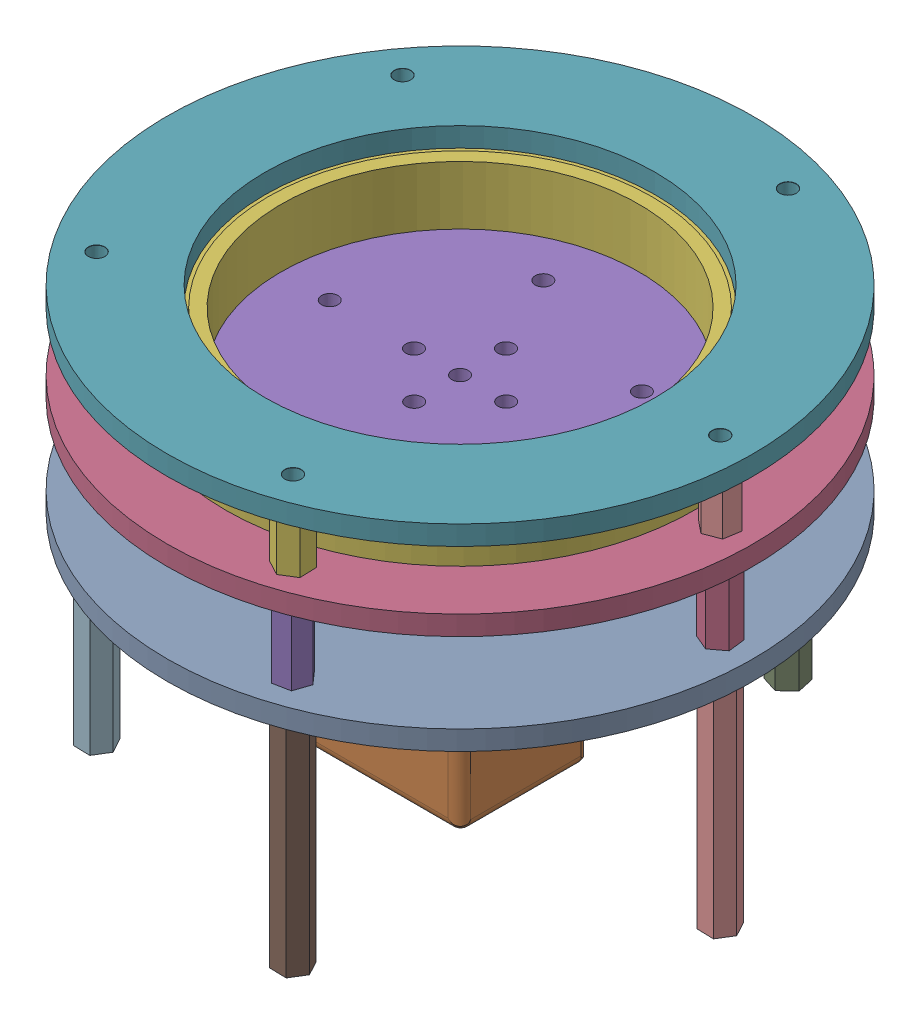
SolidWorks assembly 云台, configuration 默认. Lengths in mm.
Overall size (90 65.3 90).
22 component instances, 9 part files, 49 mates.
Components (placement in the parent):
- 底盘-1: 底盘 [默认] at (18.7397 -12.0246 45) size (90 3 90)
- 舵机td8820-1: 舵机td8820 [默认] at (8.8197 -24.5424 45) size (54.61 46.91 20)
- 舵机舵盘-1: 舵机舵盘 [默认] at (18.7397 -1.3296 45) x (0.999999 0 -0.001681) z (0.001681 0 0.999999) size (19.8 4.6 19.8)
- 云台大盘-1: 云台大盘 [默认] at (18.7397 3.2704 45) size (90 3 90)
- 云台小盘下-1: 云台小盘下 [默认] at (18.7397 6.2704 45) x (-0.999999 0 0.001681) z (0.001681 0 0.999999) size (59 3 59)
- 云台轴承-1: 云台轴承 [默认] at (18.7397 10.7704 45) size (72 9 72)
- 云台大盘-2: 云台大盘 [默认] at (18.7397 15.2704 45) size (90 3 90)
- m3+6铜柱长35-1: m3+6铜柱长35 [默认] at (-13.621 -47.0246 21.4886) x (0.476022 0 0.879433) z (0 1 0) size (5.2 4.5 41)
- m3+6铜柱长35-2: m3+6铜柱长35 [默认] at (31.1004 -47.0246 6.9577) x (0.738621 0 -0.674121) z (0 1 0) size (5.2 4.5 41)
- m3+6铜柱长35-3: m3+6铜柱长35 [默认] at (58.7397 -47.0246 45) x (0.476022 0 0.879433) z (0 1 0) size (5.2 4.5 41)
- m3+6铜柱长35-4: m3+6铜柱长35 [默认] at (31.1004 -47.0246 83.0423) x (0.476022 0 0.879433) z (0 1 0) size (5.2 4.5 41)
- m3+6铜柱长35-5: m3+6铜柱长35 [默认] at (-13.621 -47.0246 68.5114) x (0.476022 0 0.879433) z (0 1 0) size (5.2 4.5 41)
- m3+6铜柱长12-1: m3+6铜柱长12 [默认] at (31.1004 -8.7296 6.9577) x (1 0 0) z (0 1 0) size (5.2 4.5 18)
- m3+6铜柱长12-2: m3+6铜柱长12 [默认] at (-13.621 -8.7296 21.4886) x (-0.864717 0 -0.502259) z (0 1 0) size (5.2 4.5 18)
- m3+6铜柱长12-3: m3+6铜柱长12 [默认] at (-13.621 -8.7296 68.5114) x (0.977179 0 -0.212417) z (0 1 0) size (5.2 4.5 18)
- m3+6铜柱长12-4: m3+6铜柱长12 [默认] at (58.7397 -8.7296 45) x (-0.920293 0 -0.391229) z (0 1 0) size (5.2 4.5 18)
- m3+6铜柱长12-5: m3+6铜柱长12 [默认] at (31.1004 -8.7296 83.0423) x (-0.980793 0 0.195053) z (0 1 0) size (5.2 4.5 18)
- m3母铜柱长9-1: m3母铜柱长9 [默认] at (31.1004 6.2704 83.0423) x (-0.882048 0 -0.471159) z (0 1 0) size (5.2 4.5 9)
- m3母铜柱长9-2: m3母铜柱长9 [默认] at (-13.621 6.2704 21.4886) x (-0.654117 0 -0.756393) z (0 1 0) size (5.2 4.5 9)
- m3母铜柱长9-3: m3母铜柱长9 [默认] at (-13.621 6.2704 68.5114) x (-0.91723 0 -0.398357) z (0 1 0) size (5.2 4.5 9)
- m3母铜柱长9-4: m3母铜柱长9 [默认] at (31.1004 6.2704 6.9577) x (-0.720779 0 -0.693165) z (0 1 0) size (5.2 4.5 9)
- m3母铜柱长9-5: m3母铜柱长9 [默认] at (58.7397 6.2704 45) x (-0.935329 0 0.35378) z (0 1 0) size (5.2 4.5 9)
Mates (geometry in assembly coordinates):
- 重合1: coincident anti-aligned: plane of 底盘-1 through (-11.1803 -12.0246 55) normal (0 0 -1); plane of 舵机td8820-1 through (8.8197 -24.5424 55) normal (0 0 1)
- 重合2: coincident anti-aligned: plane of 底盘-1 through (-11.1803 -12.0246 35) normal (1 0 0); plane of 舵机td8820-1 through (-11.1803 -45.1346 55) normal (-1 0 0)
- 重合3: coincident anti-aligned: plane of 底盘-1 through (18.7397 -12.0246 45) normal (0 -1 0); plane of 舵机td8820-1 through (-18.4853 -12.0246 55) normal (0 1 0)
- 同心1: concentric aligned: circle of 云台轴承-1; circle of 云台大盘-2
- 同心2: concentric aligned: circle of 云台大盘-1; circle of 云台轴承-1
- 重合4: coincident anti-aligned: plane of 云台大盘-1 through (18.7397 6.2704 45) normal (0 1 0); plane of 云台轴承-1 through (18.7397 6.2704 45) normal (0 -1 0)
- 重合5: coincident anti-aligned: plane of 云台轴承-1 through (18.7397 15.2704 45) normal (0 1 0); plane of 云台大盘-2 through (18.7397 15.2704 45) normal (0 -1 0)
- 同心3: concentric aligned: circle of 云台大盘-1; circle of 云台大盘-2
- 同心4: concentric aligned: circle of 云台大盘-1; circle of 云台大盘-2
- 同心5: concentric aligned: circle of 云台大盘-1; circle of 云台大盘-2
- 相切1: tangent aligned: cylinder of 舵机舵盘-1 through (18.7397 11.0486 45) axis (0 -1 0) radius 2.75; cylinder of 舵机td8820-1 through (18.7397 -4.9296 45) axis (0 -1 0) radius 2.75
- 距离1: distance = 1 mm anti-aligned: plane of 舵机td8820-1 through (18.7397 1.7704 45) normal (0 1 0); plane of 舵机舵盘-1 through (18.7397 2.7704 45) normal (0 -1 0)
- 重合11: coincident anti-aligned: plane of 舵机舵盘-1 through (18.7397 3.2704 45) normal (0 1 0); plane of 云台小盘下-1 through (18.7397 3.2704 45) normal (0 -1 0)
- 同心6: concentric anti-aligned: circle of 舵机舵盘-1; circle of 云台小盘下-1
- 同心7: concentric anti-aligned: circle of 舵机舵盘-1; circle of 云台小盘下-1
- 重合13: coincident anti-aligned: plane of 云台小盘下-1 through (18.7397 6.2704 45) normal (0 1 0); plane of 云台轴承-1 through (18.7397 6.2704 45) normal (0 -1 0)
- 同心8: concentric anti-aligned: circle of 云台小盘下-1; circle of 云台轴承-1
- 同心9: concentric anti-aligned: circle of 底盘-1; circle of 云台大盘-1
- 同心10: concentric anti-aligned: circle of 底盘-1; circle of 云台大盘-1
- 同心11: concentric aligned: cylinder of 底盘-1 through (31.1004 -12.0246 6.9577) axis (0 -1 0) radius 1.25; cylinder of m3+6铜柱长35-2 through (31.1004 -6.0246 6.9577) axis (0 -1 0) radius 1.25
- 重合14: coincident anti-aligned: plane of 底盘-1 through (18.7397 -12.0246 45) normal (0 -1 0); plane of m3+6铜柱长35-2 through (31.1004 -12.0246 6.9577) normal (0 1 0)
- 同心12: concentric aligned: cylinder of 底盘-1 through (-13.621 -12.0246 21.4886) axis (0 -1 0) radius 1.25; cylinder of m3+6铜柱长35-1 through (-13.621 -6.0246 21.4886) axis (0 -1 0) radius 1.25
- 重合15: coincident anti-aligned: plane of 底盘-1 through (18.7397 -12.0246 45) normal (0 -1 0); plane of m3+6铜柱长35-1 through (-13.621 -12.0246 21.4886) normal (0 1 0)
- 同心14: concentric aligned: cylinder of 底盘-1 through (-13.621 -12.0246 68.5114) axis (0 -1 0) radius 1.25; cylinder of m3+6铜柱长35-5 through (-13.621 -6.0246 68.5114) axis (0 -1 0) radius 1.25
- 重合16: coincident anti-aligned: plane of 底盘-1 through (18.7397 -12.0246 45) normal (0 -1 0); plane of m3+6铜柱长35-5 through (-13.621 -12.0246 68.5114) normal (0 1 0)
- 同心15: concentric aligned: cylinder of 底盘-1 through (31.1004 -12.0246 83.0423) axis (0 -1 0) radius 1.25; cylinder of m3+6铜柱长35-4 through (31.1004 -6.0246 83.0423) axis (0 -1 0) radius 1.25
- 重合17: coincident anti-aligned: plane of 底盘-1 through (18.7397 -12.0246 45) normal (0 -1 0); plane of m3+6铜柱长35-4 through (31.1004 -12.0246 83.0423) normal (0 1 0)
- 同心16: concentric aligned: cylinder of 底盘-1 through (58.7397 -12.0246 45) axis (0 -1 0) radius 1.25; cylinder of m3+6铜柱长35-3 through (58.7397 -6.0246 45) axis (0 -1 0) radius 1.25
- 重合18: coincident anti-aligned: plane of 底盘-1 through (18.7397 -12.0246 45) normal (0 -1 0); plane of m3+6铜柱长35-3 through (58.7397 -12.0246 45) normal (0 1 0)
- 同心17: concentric aligned: cylinder of m3+6铜柱长35-3 through (58.7397 -6.0246 45) axis (0 -1 0) radius 1.25; cylinder of m3+6铜柱长12-4 through (58.7397 -8.7296 45) axis (0 -1 0) radius 1.25
- 同心18: concentric anti-aligned: cylinder of 云台大盘-1 through (31.1004 6.2704 6.9577) axis (0 1 0) radius 1.25; cylinder of m3+6铜柱长12-1 through (31.1004 9.2704 6.9577) axis (0 -1 0) radius 1.25
- 重合19: coincident anti-aligned: plane of 云台大盘-1 through (18.7397 3.2704 45) normal (0 -1 0); plane of m3+6铜柱长12-1 through (31.1004 3.2704 6.9577) normal (0 1 0)
- 重合20: coincident anti-aligned: plane of 云台大盘-1 through (18.7397 3.2704 45) normal (0 -1 0); plane of m3+6铜柱长12-4 through (58.7397 3.2704 45) normal (0 1 0)
- 同心19: concentric aligned: cylinder of m3+6铜柱长35-1 through (-13.621 -6.0246 21.4886) axis (0 -1 0) radius 1.25; cylinder of m3+6铜柱长12-2 through (-13.621 -8.7296 21.4886) axis (0 -1 0) radius 1.25
- 重合22: coincident anti-aligned: circle of m3+6铜柱长35-5; cylinder of m3+6铜柱长12-3 through (-13.621 -8.7296 68.5114) axis (0 -1 0) radius 1.25
- 重合23: coincident anti-aligned: plane of 云台大盘-1 through (18.7397 3.2704 45) normal (0 -1 0); plane of m3+6铜柱长12-3 through (-13.621 3.2704 68.5114) normal (0 1 0)
- 同心21: concentric aligned: cylinder of m3+6铜柱长35-4 through (31.1004 -6.0246 83.0423) axis (0 -1 0) radius 1.25; cylinder of m3+6铜柱长12-5 through (31.1004 -8.7296 83.0423) axis (0 -1 0) radius 1.25
- 重合24: coincident anti-aligned: plane of 云台大盘-1 through (18.7397 3.2704 45) normal (0 -1 0); plane of m3+6铜柱长12-5 through (31.1004 3.2704 83.0423) normal (0 1 0)
- 重合25: coincident anti-aligned: plane of 云台大盘-1 through (18.7397 3.2704 45) normal (0 -1 0); plane of m3+6铜柱长12-2 through (-13.621 3.2704 21.4886) normal (0 1 0)
- 同心22: concentric aligned: cylinder of m3+6铜柱长12-4 through (58.7397 9.2704 45) axis (0 -1 0) radius 1.25; cylinder of m3母铜柱长9-5 through (58.7397 6.2704 45) axis (0 -1 0) radius 1.25
- 同心23: concentric aligned: cylinder of m3+6铜柱长12-1 through (31.1004 9.2704 6.9577) axis (0 -1 0) radius 1.25; cylinder of m3母铜柱长9-4 through (31.1004 6.2704 6.9577) axis (0 -1 0) radius 1.25
- 同心24: concentric aligned: cylinder of m3+6铜柱长12-2 through (-13.621 9.2704 21.4886) axis (0 -1 0) radius 1.25; cylinder of m3母铜柱长9-2 through (-13.621 6.2704 21.4886) axis (0 -1 0) radius 1.25
- 同心25: concentric aligned: cylinder of m3+6铜柱长12-3 through (-13.621 9.2704 68.5114) axis (0 -1 0) radius 1.25; cylinder of m3母铜柱长9-3 through (-13.621 6.2704 68.5114) axis (0 -1 0) radius 1.25
- 同心26: concentric aligned: cylinder of m3+6铜柱长12-5 through (31.1004 9.2704 83.0423) axis (0 -1 0) radius 1.25; cylinder of m3母铜柱长9-1 through (31.1004 6.2704 83.0423) axis (0 -1 0) radius 1.25
- 重合26: coincident anti-aligned: plane of 云台大盘-2 through (18.7397 15.2704 45) normal (0 -1 0); plane of m3母铜柱长9-5 through (58.7397 15.2704 45) normal (0 1 0)
- 重合27: coincident anti-aligned: plane of 云台大盘-2 through (18.7397 15.2704 45) normal (0 -1 0); plane of m3母铜柱长9-4 through (31.1004 15.2704 6.9577) normal (0 1 0)
- 重合28: coincident anti-aligned: plane of 云台大盘-2 through (18.7397 15.2704 45) normal (0 -1 0); plane of m3母铜柱长9-2 through (-13.621 15.2704 21.4886) normal (0 1 0)
- 重合29: coincident anti-aligned: plane of 云台大盘-2 through (18.7397 15.2704 45) normal (0 -1 0); plane of m3母铜柱长9-3 through (-13.621 15.2704 68.5114) normal (0 1 0)
- 重合30: coincident anti-aligned: plane of 云台大盘-2 through (18.7397 15.2704 45) normal (0 -1 0); plane of m3母铜柱长9-1 through (31.1004 15.2704 83.0423) normal (0 1 0)
